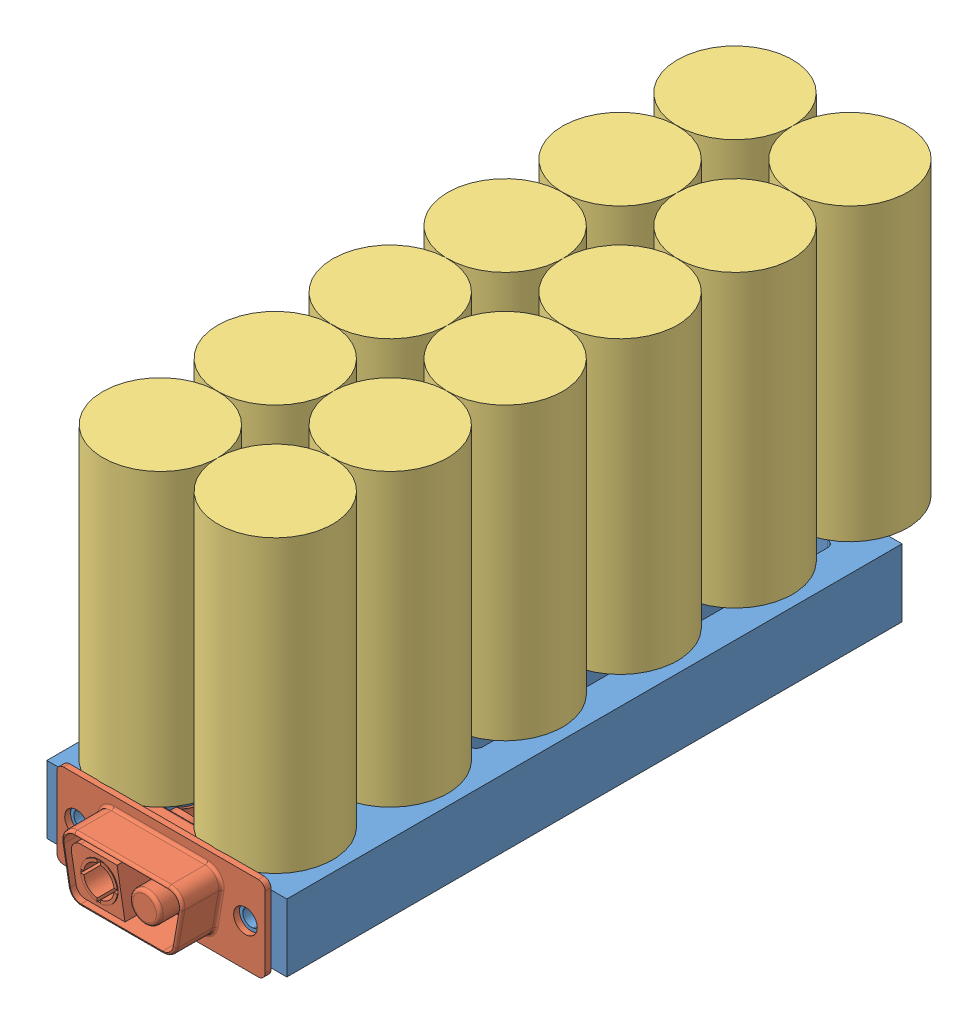
SolidWorks assembly Battery-With-Support_Assembly, configuration Default. Lengths in mm.
Overall size (35.62 54.25 108.57).
15 component instances, 3 part files, 5 mates.
Components (placement in the parent):
- BatteriesBottomSupportComplete-1: BatteriesBottomSupportComplete [Default] at (27.3209 40.5925 25.7492) size (35.5 35 91)
- DSub-25-Harting-1: DSub-25-Harting [По умолчанию] at (27.3159 40.5925 116.7492) size (30.8 12.5 18.9)
- Battery-Pack2x6-1: Battery-Pack2x6 [Défaut] at (29.2673 24.0925 94.2205) x (1 0 0) z (0 1 0) size (34 102 43)
  - Batterie-Element-1: Batterie-Element [Défaut] at (5.6828 -14.1168 21.5) size (17 17 43)
  - Batterie-Element-2: Batterie-Element [Défaut] at (-11.3172 -14.1168 21.5) size (17 17 43)
  - Batterie-Element-3: Batterie-Element [Défaut] at (5.6828 2.8832 21.5) size (17 17 43)
  - Batterie-Element-4: Batterie-Element [Défaut] at (5.6828 19.8832 21.5) size (17 17 43)
  - Batterie-Element-5: Batterie-Element [Défaut] at (5.6828 36.8832 21.5) size (17 17 43)
  - Batterie-Element-6: Batterie-Element [Défaut] at (5.6828 53.8832 21.5) size (17 17 43)
  - Batterie-Element-7: Batterie-Element [Défaut] at (5.6828 70.8832 21.5) size (17 17 43)
  - Batterie-Element-8: Batterie-Element [Défaut] at (-11.3172 2.8832 21.5) size (17 17 43)
  - Batterie-Element-9: Batterie-Element [Défaut] at (-11.3172 19.8832 21.5) size (17 17 43)
  - Batterie-Element-10: Batterie-Element [Défaut] at (-11.3172 36.8832 21.5) size (17 17 43)
  - Batterie-Element-11: Batterie-Element [Défaut] at (-11.3172 53.8832 21.5) size (17 17 43)
  - Batterie-Element-12: Batterie-Element [Défaut] at (-11.3172 70.8832 21.5) size (17 17 43)
Mates (geometry in assembly coordinates):
- Coincident1: coincident anti-aligned: plane of BatteriesBottomSupportComplete-1 through (27.3209 40.5925 116.7492) normal (0 0 1); plane of DSub-25-Harting-1 through (41.7159 45.8425 116.7492) normal (0 0 -1)
- Concentric1: concentric anti-aligned: cylinder of BatteriesBottomSupportComplete-1 through (14.8209 40.5925 96.7492) axis (0 0 1) radius 1.25; cylinder of DSub-25-Harting-1 through (14.8209 40.5925 117.6092) axis (0 0 -1) radius 1.75
- Parallel1: parallel anti-aligned: cylinder of BatteriesBottomSupportComplete-1 through (39.8209 40.5925 96.7492) axis (0 0 1) radius 1.25; cylinder of DSub-25-Harting-1 through (39.8109 40.5925 117.6092) axis (0 0 -1) radius 1.75
- Coincident2: coincident anti-aligned: plane of BatteriesBottomSupportComplete-1 through (9.5709 45.5925 116.7492) normal (0 1 0); plane of Battery-Pack2x6-1/Batterie-Element-7 through (34.95 45.5925 23.3373) normal (0 -1 0)
- Parallel2: parallel anti-aligned: plane of DSub-25-Harting-1 through (41.7159 45.8425 117.6092) normal (0 0 1); plane of Battery-Pack2x6-1 through (29.2673 24.0925 94.2205) normal (0 0 -1)
